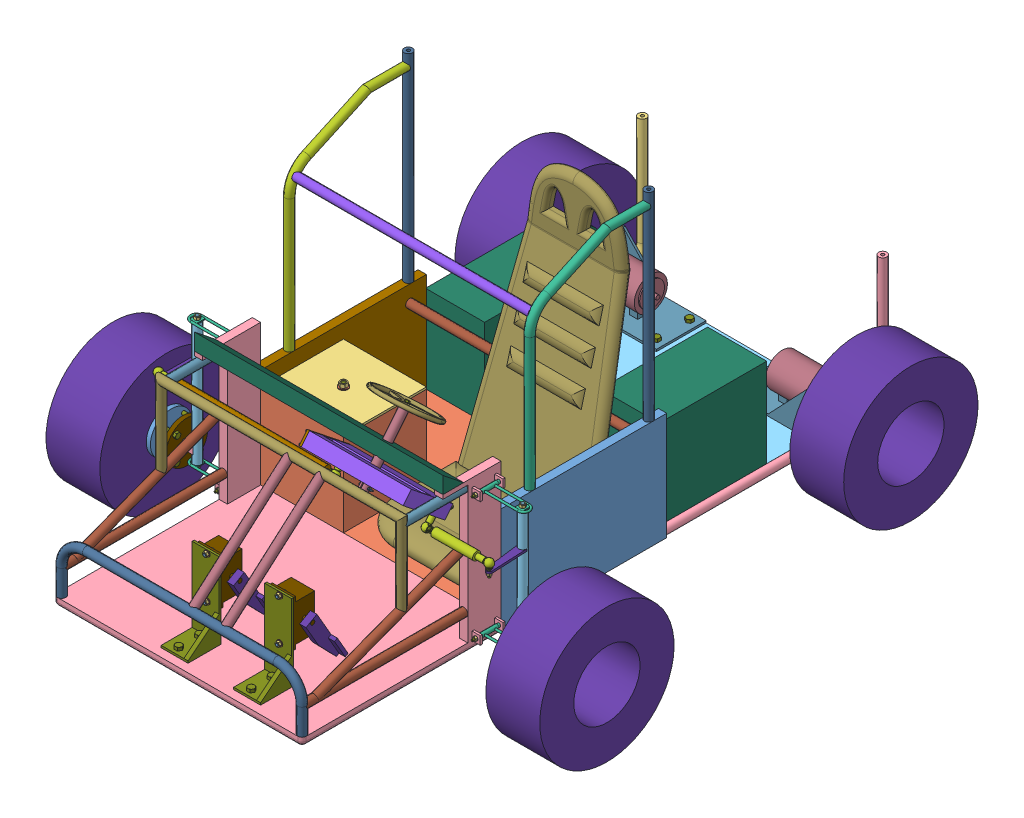
SolidWorks assembly Full_Assembly_2.0, configuration Default. Lengths in mm.
Overall size (1513.16 1181.12 1856.74).
253 component instances, 57 part files, 73 mates.
Components (placement in the parent):
- MC (1)-1: MC (1) [Default] at (-134.0082 207.4417 1496.2137) size (1191.26 1083.62 1343.85)
  - SPL-1: SPL [Default] at (646.5449 178.7927 -996.551) size (25.4 330.2 508)
  - BP-1: BP [Default] at (111.0665 -124.6065 -917.4807) size (711.2 25.4 508)
  - BBR-2: BBR [Default] at (-77.3551 -47.0728 -1647.3326) x (-1 0 0) z (0 -1 0) size (25.4 687.13 407.73)
  - BBL-1: BBL [Default] at (659.2449 -47.0728 -1647.3326) x (-1 0 0) z (0 -1 0) size (25.4 687.13 407.73)
  - BC-1: BC [Default] at (357.2961 -116.9228 -1647.3326) x (-1 0 0) z (0 0 -1) size (723.9 12.7 609.6)
  - FTL-1: FTL [Default] at (659.245 611.9935 -719.4116) x (0 -0.899323 -0.437285) z (-1 0 -0.000001) size (433.75 589.6 27.41)
  - FTR-1: FTR [Default] at (-77.355 611.9935 -719.4116) x (0 -0.899323 -0.437285) z (-1 0 -0.000001) size (433.75 589.6 27.38)
  - TC-1: TC [Default] at (652.8949 660.2535 -644.2461) x (0 -0.542655 -0.839955) z (-1 0 -0.000001) size (25.4 25.4 723.9)
  - SPR-1: SPR [Default] at (-90.0551 178.7927 -996.551) size (25.4 330.2 508)
  - BT-1: BT [Default] at (-77.3551 205.5935 -995.2506) x (0.000001 0 -1) z (1 0 0.000001) size (25.4 609.6 25.4)
  - BT-2: BT [Default] at (659.2449 205.5935 -995.2506) x (0.000001 0 -1) z (1 0 0.000001) size (25.4 609.6 25.4)
  - FB-1: FB [Default] at (-71.0051 154.7935 -986.9326) x (1 0 0) z (0 0.990518 0.137381) size (723.9 25.4 25.4)
  - seat-1: seat [Default] at (418.0013 -99.2065 -848.8249) size (437.03 835.23 478.09)
  - EA1-1: EA1 [Default] at (125.7912 -160.5315 -1631.3403) x (0 0 1) z (-1 0 0) size (411.48 411.48 1349.16)
    - EB1-1: EB1 [Default] at (60.2077 126.1588 196.7963) size (101.6 101.6 238.25)
    - EP1-1: EP1 [Default] at (60.2077 56.3088 69.7963) x (0 0 1) z (-1 0 0) size (254 133.35 152.4)
    - EA2-1: EA2 [Default] at (45.9187 58.6487 138.5565) size (411.48 411.48 213.36)
      - EP2-1: EP2 [Default] at (14.289 67.5101 114.1198) size (127 127 48.26)
      - hex bolt_ai-1: hex bolt_ai [HBOLT 0.4375-20x1.375x1.125-N] at (-36.511 67.5101 106.0934) x (0 0 1) z (-0.866025 -0.5 0) size (42.95 18.33 15.88)
      - hex bolt_ai-2: hex bolt_ai [HBOLT 0.4375-20x1.375x1.125-N] at (14.289 118.3101 106.0934) x (0 0 1) z (0 -1 0) size (42.95 18.33 15.88)
      - hex bolt_ai-3: hex bolt_ai [HBOLT 0.4375-20x1.375x1.125-N] at (14.289 16.7101 106.0934) x (0 0 1) z (-0.866025 0.5 0) size (42.95 18.33 15.88)
      - hex bolt_ai-4: hex bolt_ai [HBOLT 0.4375-20x1.375x1.125-N] at (65.089 67.5101 106.0934) x (0 0 1) z (-0.866025 0.5 0) size (42.95 18.33 15.88)
      - EB2-1: EB2 [Default] at (14.289 67.5101 129.9948) x (-1 0 0) z (0 0 -1) size (411.48 411.48 165.1)
      - flat washer type a wide_ai-1: flat washer type a wide_ai [Preferred Wide FW 0.4375] at (-36.511 67.5101 132.103) x (0 0 1) z (-0.923728 -0.383049 0) size (2.11 31.75 31.75)
      - flat washer type a wide_ai-2: flat washer type a wide_ai [Preferred Wide FW 0.4375] at (14.289 118.3101 132.103) x (0 0 1) z (1 0 0) size (2.11 31.75 31.75)
      - flat washer type a wide_ai-3: flat washer type a wide_ai [Preferred Wide FW 0.4375] at (14.289 16.7101 132.103) x (0 0 1) z (1 0 0) size (2.11 31.75 31.75)
      - flat washer type a wide_ai-4: flat washer type a wide_ai [Preferred Wide FW 0.4375] at (65.089 67.5101 132.103) x (0 0 1) z (1 0 0) size (2.11 31.75 31.75)
      - hex thick nut_ai-1: hex thick nut_ai [HTNUT 0.4375-14-D-N] at (14.289 16.7101 143.8632) x (0.055202 -0.998475 0) z (0 0 1) size (17.48 20.18 11.76)
      - hex thick nut_ai-2: hex thick nut_ai [HTNUT 0.4375-14-D-N] at (-36.511 67.5101 143.8632) x (0.547044 -0.837104 0) z (0 0 1) size (17.48 20.18 11.76)
      - hex thick nut_ai-3: hex thick nut_ai [HTNUT 0.4375-14-D-N] at (65.089 67.5101 143.8632) x (-0.982324 -0.18719 0) z (0 0 1) size (17.48 20.18 11.76)
      - hex thick nut_ai-4: hex thick nut_ai [HTNUT 0.4375-14-D-N] at (14.289 118.3101 143.8632) x (0.055202 -0.998475 0) z (0 0 1) size (17.48 20.18 11.76)
    - hex bolt_ai-8: hex bolt_ai [HBOLT 0.3125-18x1.375x0.875-N] at (17.0277 169.3388 215.4653) x (0 0 -1) z (0 1 0) size (40.89 14.66 12.7)
    - hex bolt_ai-9: hex bolt_ai [HBOLT 0.3125-18x1.375x0.875-N] at (103.3877 169.3388 215.4653) x (0 0 -1) z (0.866025 -0.5 0) size (40.89 14.66 12.7)
    - hex bolt_ai-10: hex bolt_ai [HBOLT 0.3125-18x1.375x0.875-N] at (103.3877 82.9788 215.4653) x (0 0 -1) z (0.866025 0.5 0) size (40.89 14.66 12.7)
    - hex bolt_ai-11: hex bolt_ai [HBOLT 0.3125-18x1.375x0.875-N] at (17.0277 82.9788 215.4653) x (0 0 -1) z (-0.866025 -0.5 0) size (40.89 14.66 12.7)
    - flat washer type a narrow_ai-1: flat washer type a narrow_ai [Preferred Narrow FW 0.3125] at (17.0277 169.3388 190.4463) x (0 0 1) z (-1 0 0) size (1.65 17.48 17.48)
    - flat washer type a narrow_ai-2: flat washer type a narrow_ai [Preferred Narrow FW 0.3125] at (103.3877 82.9788 190.4463) x (0 0 1) z (-1 0 0) size (1.65 17.48 17.48)
    - flat washer type a narrow_ai-3: flat washer type a narrow_ai [Preferred Narrow FW 0.3125] at (17.0277 82.9788 188.7953) x (0 0 -1) z (1 0 0) size (1.65 17.48 17.48)
    - flat washer type a narrow_ai-4: flat washer type a narrow_ai [Preferred Narrow FW 0.3125] at (103.3877 169.3388 188.7953) x (0 0 -1) z (0.923728 0.383049 0) size (1.65 17.48 17.48)
    - hex thick nut_ai-1: hex thick nut_ai [HTNUT 0.3125-18-D-N] at (103.3877 169.3388 188.7953) x (0.866025 0.5 0) z (0 0 1) size (12.7 14.66 8.53)
    - hex thick nut_ai-2: hex thick nut_ai [HTNUT 0.3125-18-D-N] at (17.0277 82.9788 180.2609) x (-0.866025 0.5 0) z (0 0 -1) size (12.7 14.66 8.53)
    - hex thick nut_ai-3: hex thick nut_ai [HTNUT 0.3125-18-D-N] at (103.3877 82.9788 181.9119) x (-0.866025 -0.5 0) z (0 0 -1) size (12.7 14.66 8.53)
    - hex thick nut_ai-4: hex thick nut_ai [HTNUT 0.3125-18-D-N] at (17.0277 169.3388 180.2609) x (-0.866025 -0.5 0) z (0 0 -1) size (12.7 14.66 8.53)
  - EA1-2: EA1 [Default] at (456.0986 -160.5315 -1510.9249) x (0 0 -1) z (1 0 0) size (411.48 411.48 1349.16)
    - EB1-1: EB1 [Default] at (60.2077 126.1588 196.7963) size (101.6 101.6 238.25)
    - EP1-1: EP1 [Default] at (60.2077 56.3088 69.7963) x (0 0 1) z (-1 0 0) size (254 133.35 152.4)
    - EA2-1: EA2 [Default] at (45.9187 58.6487 138.5565) size (411.48 411.48 213.36)
      - EP2-1: EP2 [Default] at (14.289 67.5101 114.1198) size (127 127 48.26)
      - hex bolt_ai-1: hex bolt_ai [HBOLT 0.4375-20x1.375x1.125-N] at (-36.511 67.5101 106.0934) x (0 0 1) z (-0.866025 -0.5 0) size (42.95 18.33 15.88)
      - hex bolt_ai-2: hex bolt_ai [HBOLT 0.4375-20x1.375x1.125-N] at (14.289 118.3101 106.0934) x (0 0 1) z (0 -1 0) size (42.95 18.33 15.88)
      - hex bolt_ai-3: hex bolt_ai [HBOLT 0.4375-20x1.375x1.125-N] at (14.289 16.7101 106.0934) x (0 0 1) z (-0.866025 0.5 0) size (42.95 18.33 15.88)
      - hex bolt_ai-4: hex bolt_ai [HBOLT 0.4375-20x1.375x1.125-N] at (65.089 67.5101 106.0934) x (0 0 1) z (-0.866025 0.5 0) size (42.95 18.33 15.88)
      - EB2-1: EB2 [Default] at (14.289 67.5101 129.9948) x (-1 0 0) z (0 0 -1) size (411.48 411.48 165.1)
      - flat washer type a wide_ai-1: flat washer type a wide_ai [Preferred Wide FW 0.4375] at (-36.511 67.5101 132.103) x (0 0 1) z (-0.923728 -0.383049 0) size (2.11 31.75 31.75)
      - flat washer type a wide_ai-2: flat washer type a wide_ai [Preferred Wide FW 0.4375] at (14.289 118.3101 132.103) x (0 0 1) z (1 0 0) size (2.11 31.75 31.75)
      - flat washer type a wide_ai-3: flat washer type a wide_ai [Preferred Wide FW 0.4375] at (14.289 16.7101 132.103) x (0 0 1) z (1 0 0) size (2.11 31.75 31.75)
      - flat washer type a wide_ai-4: flat washer type a wide_ai [Preferred Wide FW 0.4375] at (65.089 67.5101 132.103) x (0 0 1) z (1 0 0) size (2.11 31.75 31.75)
      - hex thick nut_ai-1: hex thick nut_ai [HTNUT 0.4375-14-D-N] at (14.289 16.7101 143.8632) x (0.055202 -0.998475 0) z (0 0 1) size (17.48 20.18 11.76)
      - hex thick nut_ai-2: hex thick nut_ai [HTNUT 0.4375-14-D-N] at (-36.511 67.5101 143.8632) x (0.547044 -0.837104 0) z (0 0 1) size (17.48 20.18 11.76)
      - hex thick nut_ai-3: hex thick nut_ai [HTNUT 0.4375-14-D-N] at (65.089 67.5101 143.8632) x (-0.982324 -0.18719 0) z (0 0 1) size (17.48 20.18 11.76)
      - hex thick nut_ai-4: hex thick nut_ai [HTNUT 0.4375-14-D-N] at (14.289 118.3101 143.8632) x (0.055202 -0.998475 0) z (0 0 1) size (17.48 20.18 11.76)
    - hex bolt_ai-8: hex bolt_ai [HBOLT 0.3125-18x1.375x0.875-N] at (17.0277 169.3388 215.4653) x (0 0 -1) z (0 1 0) size (40.89 14.66 12.7)
    - hex bolt_ai-9: hex bolt_ai [HBOLT 0.3125-18x1.375x0.875-N] at (103.3877 169.3388 215.4653) x (0 0 -1) z (0.866025 -0.5 0) size (40.89 14.66 12.7)
    - hex bolt_ai-10: hex bolt_ai [HBOLT 0.3125-18x1.375x0.875-N] at (103.3877 82.9788 215.4653) x (0 0 -1) z (0.866025 0.5 0) size (40.89 14.66 12.7)
    - hex bolt_ai-11: hex bolt_ai [HBOLT 0.3125-18x1.375x0.875-N] at (17.0277 82.9788 215.4653) x (0 0 -1) z (-0.866025 -0.5 0) size (40.89 14.66 12.7)
    - flat washer type a narrow_ai-1: flat washer type a narrow_ai [Preferred Narrow FW 0.3125] at (17.0277 169.3388 190.4463) x (0 0 1) z (-1 0 0) size (1.65 17.48 17.48)
    - flat washer type a narrow_ai-2: flat washer type a narrow_ai [Preferred Narrow FW 0.3125] at (103.3877 82.9788 190.4463) x (0 0 1) z (-1 0 0) size (1.65 17.48 17.48)
    - flat washer type a narrow_ai-3: flat washer type a narrow_ai [Preferred Narrow FW 0.3125] at (17.0277 82.9788 188.7953) x (0 0 -1) z (1 0 0) size (1.65 17.48 17.48)
    - flat washer type a narrow_ai-4: flat washer type a narrow_ai [Preferred Narrow FW 0.3125] at (103.3877 169.3388 188.7953) x (0 0 -1) z (0.923728 0.383049 0) size (1.65 17.48 17.48)
    - hex thick nut_ai-1: hex thick nut_ai [HTNUT 0.3125-18-D-N] at (103.3877 169.3388 188.7953) x (0.866025 0.5 0) z (0 0 1) size (12.7 14.66 8.53)
    - hex thick nut_ai-2: hex thick nut_ai [HTNUT 0.3125-18-D-N] at (17.0277 82.9788 180.2609) x (-0.866025 0.5 0) z (0 0 -1) size (12.7 14.66 8.53)
    - hex thick nut_ai-3: hex thick nut_ai [HTNUT 0.3125-18-D-N] at (103.3877 82.9788 181.9119) x (-0.866025 -0.5 0) z (0 0 -1) size (12.7 14.66 8.53)
    - hex thick nut_ai-4: hex thick nut_ai [HTNUT 0.3125-18-D-N] at (17.0277 169.3388 180.2609) x (-0.866025 -0.5 0) z (0 0 -1) size (12.7 14.66 8.53)
  - hex bolt_ai-1: hex bolt_ai [HBOLT 0.5000-13x1.375x1.25-N] at (157.5949 -88.6272 -1621.9326) x (0 -1 0) z (-1 0 0) size (44.17 22 19.05)
  - hex bolt_ai-2: hex bolt_ai [HBOLT 0.5000-13x1.375x1.25-N] at (157.5949 -88.6272 -1520.3326) x (0 -1 0) z (0.5 0 -0.866025) size (44.17 22 19.05)
  - hex bolt_ai-3: hex bolt_ai [HBOLT 0.5000-13x1.375x1.25-N] at (424.2949 -88.6272 -1520.3326) x (0 -1 0) z (1 0 0) size (44.17 22 19.05)
  - hex bolt_ai-4: hex bolt_ai [HBOLT 0.5000-13x1.375x1.25-N] at (602.0949 -88.6272 -1621.9326) x (0 -1 0) z (-0.5 0 -0.866025) size (44.17 22 19.05)
  - hex bolt_ai-5: hex bolt_ai [HBOLT 0.5000-13x1.375x1.25-N] at (424.2949 -88.6272 -1621.9326) x (0 -1 0) z (0.5 0 -0.866025) size (44.17 22 19.05)
  - hex bolt_ai-6: hex bolt_ai [HBOLT 0.5000-13x1.375x1.25-N] at (602.0949 -88.6272 -1520.3326) x (0 -1 0) z (-0.5 0 0.866025) size (44.17 22 19.05)
  - hex bolt_ai-7: hex bolt_ai [HBOLT 0.5000-13x1.375x1.25-N] at (-20.2051 -88.6272 -1621.9326) x (0 -1 0) z (-1 0 0) size (44.17 22 19.05)
  - hex bolt_ai-8: hex bolt_ai [HBOLT 0.5000-13x1.375x1.25-N] at (-20.2051 -88.6272 -1520.3326) x (0 -1 0) z (1 0 0) size (44.17 22 19.05)
  - flat washer type a wide_ai-1: flat washer type a wide_ai [Preferred Wide FW 0.5] at (157.5949 -119.6914 -1520.3326) x (0 -1 0) z (0.546944 0 -0.837169) size (2.77 34.92 34.92)
  - flat washer type a wide_ai-2: flat washer type a wide_ai [Preferred Wide FW 0.5] at (157.5949 -119.6914 -1621.9326) x (0 -1 0) z (0.967366 0 0.253384) size (2.77 34.92 34.92)
  - flat washer type a wide_ai-3: flat washer type a wide_ai [Preferred Wide FW 0.5] at (424.2949 -119.6914 -1621.9326) x (0 -1 0) z (-0.558017 0 -0.829829) size (2.77 34.92 34.92)
  - flat washer type a wide_ai-4: flat washer type a wide_ai [Preferred Wide FW 0.5] at (-20.2051 -119.6914 -1520.3326) x (0 -1 0) z (0.590888 0 -0.806754) size (2.77 34.92 34.92)
  - flat washer type a wide_ai-5: flat washer type a wide_ai [Preferred Wide FW 0.5] at (602.0949 -119.6914 -1520.3326) x (0 -1 0) z (0.610265 0 -0.792197) size (2.77 34.92 34.92)
  - flat washer type a wide_ai-6: flat washer type a wide_ai [Preferred Wide FW 0.5] at (424.2949 -119.6914 -1520.3326) x (0 -1 0) z (0.837672 0 -0.546174) size (2.77 34.92 34.92)
  - flat washer type a wide_ai-7: flat washer type a wide_ai [Preferred Wide FW 0.5] at (602.0949 -119.6914 -1621.9326) x (0 -1 0) z (0.97172 0 -0.236136) size (2.77 34.92 34.92)
  - flat washer type a wide_ai-8: flat washer type a wide_ai [Preferred Wide FW 0.5] at (-20.2051 -119.6914 -1621.9326) x (0 -1 0) z (0.345214 0 -0.938524) size (2.77 34.92 34.92)
  - hex nut_ai-1: hex nut_ai [HNUT 0.5000-13-D-N] at (157.5949 -131.0706 -1520.3326) x (-0.5 0 -0.866025) z (0 -1 0) size (19.05 22 11.38)
  - hex nut_ai-2: hex nut_ai [HNUT 0.5000-13-D-N] at (-20.2051 -131.0706 -1621.9326) x (-0.866025 0 -0.5) z (0 -1 0) size (19.05 22 11.38)
  - hex nut_ai-3: hex nut_ai [HNUT 0.5000-13-D-N] at (-20.2051 -131.0706 -1520.3326) x (0 0 -1) z (0 -1 0) size (19.05 22 11.38)
  - hex nut_ai-4: hex nut_ai [HNUT 0.5000-13-D-N] at (157.5949 -131.0706 -1621.9326) x (0 0 -1) z (0 -1 0) size (19.05 22 11.38)
  - hex nut_ai-5: hex nut_ai [HNUT 0.5000-13-D-N] at (424.2949 -131.0706 -1520.3326) x (0 0 1) z (0 -1 0) size (19.05 22 11.38)
  - hex nut_ai-6: hex nut_ai [HNUT 0.5000-13-D-N] at (424.2949 -131.0706 -1621.9326) x (-0.866025 0 0.5) z (0 -1 0) size (19.05 22 11.38)
  - hex nut_ai-8: hex nut_ai [HNUT 0.5000-13-D-N] at (602.0949 -131.0706 -1520.3326) x (-0.866025 0 -0.5) z (0 -1 0) size (19.05 22 11.38)
  - hex nut_ai-9: hex nut_ai [HNUT 0.5000-13-D-N] at (602.0949 -131.0706 -1621.9326) x (-0.866025 0 -0.5) z (0 -1 0) size (19.05 22 11.38)
  - hex bolt_ai-11: hex bolt_ai [HBOLT 0.5000-13x3x1.25-N] at (62.3449 -133.8521 -656.7326) x (0 1 0) z (-0.5 0 0.866025) size (85.45 22 19.05)
  - flat washer type a narrow_ai-1: flat washer type a narrow_ai [Preferred Narrow FW 0.5] at (62.3449 -99.2065 -656.7326) x (0 -1 0) z (0 0 1) size (2.41 26.97 26.97)
  - hex nut_ai-10: hex nut_ai [HNUT 0.5000-13-D-N] at (62.3449 -87.8273 -656.7326) x (1 0 0) z (0 1 0) size (19.05 22 11.38)
- FCA1-1: FCA1 [Default] at (-224.0632 159.0352 1576.0811) size (1513.16 852.83 849.49)
  - FCP1-1: FCP1 [Default] at origin size (812.8 457.2 609.6)
  - STA1-2: STA1 [Default] at (558.8 334.6162 -409.4012) x (-0.999987 0.003219 0.004024) z (0 0.780869 -0.624695) size (320.68 259.28 240.21)
    - STP10-3: STP10 [Default] at origin size (304.8 155.79 25.4)
      - spur gear_ai-4: spur gear_ai [Inch - Spur gear 6DP 25T 20PA 1FW ---S25N3.0H2.0L1.0S1] x (0 0 1) z (-0.989908 0.141715 0) size (25.4 113.98 114.2)
      - rack spur rectangular_ai-2: rack spur rectangular_ai [Inch - Rack-spur - rectangular 6DP 20PA 1FW 1.5PH 12L---SAll] at (-154.037 -91.44 25.4) size (304.8 42.33 25.4)
    - STP01-11: STP01 [Default] at (138.063 -75.0375 -39.3517) x (0 1 0) z (0 0 -1) size (23.88 20.07 47.75)
    - STP03-3: STP03 [Default] at (150.763 -97.79 31.75) x (0 0 -1) z (1 0 0) size (39.69 165.1 311.15)
    - STP04-3: STP04 [Default] at (150.763 -97.79 -7.9375) x (0 0 1) z (-1 0 0) size (39.69 165.1 6.59)
    - socket head cap screw_ai-1: socket head cap screw_ai [HX-SHCS 0.125-40x0.5x0.5-N] at (160.288 64.135 28.575) x (-1 0 0) z (0 0.866025 0.5) size (15.88 5.21 5.21)
    - socket head cap screw_ai-2: socket head cap screw_ai [HX-SHCS 0.125-40x0.5x0.5-N] at (160.288 64.135 -4.7625) x (-1 0 0) z (0 0.866025 0.5) size (15.88 5.21 5.21)
    - socket head cap screw_ai-4: socket head cap screw_ai [HX-SHCS 0.125-40x0.5x0.5-N] at (160.288 -94.615 28.575) x (-1 0 0) z (0 0.866025 0.5) size (15.88 5.21 5.21)
    - socket head cap screw_ai-7: socket head cap screw_ai [HX-SHCS 0.125-40x0.5x0.5-N] at (160.288 -94.615 -4.7625) x (-1 0 0) z (0 0.866025 0.5) size (15.88 5.21 5.21)
    - STP01-10: STP01 [Default] at (-141.337 -75.0375 -39.3517) x (0 -1 0) z (0 0 -1) size (23.88 20.07 47.75)
    - STP05-2: STP05 [Default] at (-154.037 -58.6317 0) x (1 0 0) z (0 0 -1) size (304.8 32.77 26.99)
    - STP06-1: STP06 [Default] at (-0.0036 -0.0251 180.975) x (0.5 -0.866025 0) z (0 0 1) size (189.81 189.81 12.01)
    - STP07-1: STP07 [Default] at (-0.0036 -0.0251 -33.528) x (-0.141715 -0.989908 0) z (0 0 1) size (28 24.77 211.33)
    - FWP4-1: FWP4 [Default] at (-20.7057 3.2593 -20.828) x (0 0 1) z (0.989908 -0.141715 0) size (12.7 12.7 39.95)
    - hex bolt_ai-1: hex bolt_ai [HBOLT 0.2500-20x0.75x0.75-N] at (-0.0036 -0.0251 188.9252) x (0 0 -1) z (0.5 0.866025 0) size (23.83 12.85 11.13)
  - STP08-1: STP08 [Default] at (469.9 381 -431.8) x (0 0 -1) z (1 0 0) size (63.5 50.8 762)
  - STP02-1: STP02 [Default] at (889.5958 256.5577 -445.8437) x (-0.961205 0 0.275836) z (0 1 0) size (16.51 16.51 46.05)
  - SP3-1: SP3 [Default] at (889.5958 238.8316 -445.8437) x (-0.086724 0 -0.996232) z (0 -1 0) size (120.39 25.32 6.35)
  - FWA1-1: FWA1 [Default] at (1025.989 75.5387 -589.4868) x (0 -0.682582 -0.730809) z (-1 0 0) size (411.48 411.48 257.81)
    - FWP5-2: FWP5 [Default] at (27.9791 75.0582 101.7677) size (127 127 48.26)
    - FWP1-1: FWP1 [Default] at (27.9791 75.0582 53.5077) size (127 127 48.26)
    - EB2-1: EB2 [Default] at (27.9791 75.0582 50.3327) x (-1 0 0) z (0 0 1) size (411.48 411.48 165.1)
    - internal tooth-lock washers_ai-1: internal tooth-lock washers_ai [Internal Tooth LW Type A-0.375] at (78.7791 75.0582 49.3167) x (0.992449 -0.122662 0) z (-0.122662 -0.992449 0) size (17.58 1.02 17.58)
    - internal tooth-lock washers_ai-2: internal tooth-lock washers_ai [Internal Tooth LW Type A-0.375] at (-22.8209 75.0582 49.3167) x (0.730809 -0.682582 0) z (-0.682582 -0.730809 0) size (17.58 1.02 17.58)
    - FWP2-2: FWP2 [Default] at (27.9791 75.0582 114.4677) x (-0.730809 0.682582 0) z (0 0 -1) size (9.53 9.53 14.29)
    - FWP3-2: FWP3 [Default] at (19.3103 65.7769 130.3427) x (0 0 1) z (-0.730809 0.682582 0) size (31.75 25.4 25.4)
    - FWP4-1: FWP4 [Default] at (13.8923 59.9761 123.9927) x (-0.730809 0.682582 0) z (0.682582 0.730809 0) size (12.7 12.7 39.95)
    - hex nut_ai-5: hex nut_ai [HNUT 0.4375-20-D-N] at (78.7791 75.0582 49.3167) x (0.291608 -0.956538 0) z (0 0 1) size (17.48 20.18 9.78)
    - internal tooth-lock washers_ai-5: internal tooth-lock washers_ai [Internal Tooth LW Type A-0.375] at (27.9791 24.2582 49.3167) x (-0.875007 -0.484111 0) z (-0.484111 0.875007 0) size (17.58 1.02 17.58)
    - internal tooth-lock washers_ai-6: internal tooth-lock washers_ai [Internal Tooth LW Type A-0.375] at (27.9791 125.8582 49.3167) x (0.730809 -0.682582 0) z (-0.682582 -0.730809 0) size (17.58 1.02 17.58)
    - hex nut_ai-7: hex nut_ai [HNUT 0.4375-20-D-N] at (-22.8209 75.0582 49.3167) x (0.291608 -0.956538 0) z (0 0 1) size (17.48 20.18 9.78)
    - hex nut_ai-8: hex nut_ai [HNUT 0.4375-20-D-N] at (27.9791 24.2582 39.5377) x (-0.97419 0.225729 0) z (0 0 -1) size (17.48 20.18 9.78)
    - hex nut_ai-9: hex nut_ai [HNUT 0.4375-20-D-N] at (27.9791 125.8582 49.3167) x (-0.97419 0.225729 0) z (0 0 1) size (17.48 20.18 9.78)
    - hex bolt_ai-1: hex bolt_ai [HBOLT 0.4375-20x3x1.125-N] at (78.7791 75.0582 122.4941) x (0 0 -1) z (-0.291608 0.956538 0) size (84.23 18.33 15.88)
    - hex bolt_ai-2: hex bolt_ai [HBOLT 0.4375-20x3x1.125-N] at (27.9791 125.8582 122.4941) x (0 0 -1) z (0.682582 0.730809 0) size (84.23 18.33 15.88)
    - hex bolt_ai-3: hex bolt_ai [HBOLT 0.4375-20x3x1.125-N] at (-22.8209 75.0582 122.4941) x (0 0 -1) z (0.97419 -0.225729 0) size (84.23 18.33 15.88)
    - hex bolt_ai-6: hex bolt_ai [HBOLT 0.4375-20x3x1.125-N] at (27.9791 24.2582 122.4941) x (0 0 -1) z (0.97419 -0.225729 0) size (84.23 18.33 15.88)
  - SA1-3: SA1 [Default] at (902.3249 84.601 -573.897) x (-0.581832 0 -0.813309) z (0 1 0) size (129.23 145.39 403.48)
    - SS1-1: SS1 [Default] at (0.7633 27.1847 256.5845) x (1 0 0) z (0 0 1) size (25.4 25.4 403.48)
    - SP2-2: SP2 [Default] at (87.3872 94.4048 258.172) x (0.581832 0.813309 0) z (-0.813309 0.581832 0) size (133.34 12.7 63.5)
    - SP2-3: SP2 [Default] at (87.3872 94.4048 -122.701) x (0.581832 0.813309 0) z (-0.813309 0.581832 0) size (133.34 12.7 63.5)
    - hex nut_ai-3: hex nut_ai [HNUT 0.3750-24-D-N] at (0.7633 27.1846 -132.8483) x (0.910536 0.41343 0) z (0 0 -1) size (14.27 16.48 8.56)
    - hex nut_ai-4: hex nut_ai [HNUT 0.3750-24-D-N] at (0.7633 27.1847 268.3193) x (0.910536 0.41343 0) z (0 0 1) size (14.27 16.48 8.56)
  - STP09-1: STP09 [Default] at (724.7148 240.1747 -456.9263) x (0.009813 0 0.999952) z (-0.999952 0 0.009813) size (25.4 25.4 152.4)
  - STP02-2: STP02 [Default] at (699.7485 256.5577 -443.9807) x (-0.004906 -0.866025 -0.499976) z (-0.999952 0 0.009813) size (16.51 16.51 46.05)
  - STP01-3: STP01 [Default] at (889.5958 256.5577 -445.8437) x (0.009813 0 0.999952) z (0.999952 0 -0.009813) size (23.88 20.07 47.75)
  - hex bolt_ai-1: hex bolt_ai [HBOLT 0.2500-20x3.5x0.75-N] at (774.7 342.9 -601.6752) x (0 0 1) z (-1 0 0) size (93.68 12.85 11.13)
  - external tooth lock washer_ai-1: external tooth lock washer_ai [ASME B18.21.1 - 0.256] at (774.7 342.9 -520.7) x (0 0 -1) z (0.999649 0.026486 0) size (0.58 12.4 12.55)
  - hex nut_ai-1: hex nut_ai [HNUT 0.2500-28-D-N] at (774.7 342.9 -514.3754) x (0.5 -0.866025 0) z (0 0 1) size (11.11 12.83 5.74)
  - hex bolt_ai-2: hex bolt_ai [HBOLT 0.2500-20x3.5x0.75-N] at (774.7 -38.1 -601.6752) x (0 0 1) z (-0.5 0.866025 0) size (93.68 12.85 11.13)
  - external tooth lock washer_ai-2: external tooth lock washer_ai [ASME B18.21.1 - 0.256] at (774.7 -38.1 -520.7) x (0 0 -1) z (0.643979 -0.765044 0) size (0.58 12.4 12.55)
  - hex nut_ai-2: hex nut_ai [HNUT 0.2500-28-D-N] at (774.7 -38.1 -514.3754) x (0.5 -0.866025 0) z (0 0 1) size (11.11 12.83 5.74)
  - FWA1-2: FWA1 [Default] at (-263.989 -72.2367 -589.4868) x (0 0.682582 -0.730809) z (1 0 0) size (411.48 411.48 257.81)
    - FWP5-2: FWP5 [Default] at (27.9791 75.0582 101.7677) size (127 127 48.26)
    - FWP1-1: FWP1 [Default] at (27.9791 75.0582 53.5077) size (127 127 48.26)
    - EB2-1: EB2 [Default] at (27.9791 75.0582 50.3327) x (-1 0 0) z (0 0 1) size (411.48 411.48 165.1)
    - internal tooth-lock washers_ai-1: internal tooth-lock washers_ai [Internal Tooth LW Type A-0.375] at (78.7791 75.0582 49.3167) x (0.992449 -0.122662 0) z (-0.122662 -0.992449 0) size (17.58 1.02 17.58)
    - internal tooth-lock washers_ai-2: internal tooth-lock washers_ai [Internal Tooth LW Type A-0.375] at (-22.8209 75.0582 49.3167) x (0.730809 -0.682582 0) z (-0.682582 -0.730809 0) size (17.58 1.02 17.58)
    - FWP2-2: FWP2 [Default] at (27.9791 75.0582 114.4677) x (-0.730809 0.682582 0) z (0 0 -1) size (9.53 9.53 14.29)
    - FWP3-2: FWP3 [Default] at (19.3103 65.7769 130.3427) x (0 0 1) z (-0.730809 0.682582 0) size (31.75 25.4 25.4)
    - FWP4-1: FWP4 [Default] at (13.8923 59.9761 123.9927) x (-0.730809 0.682582 0) z (0.682582 0.730809 0) size (12.7 12.7 39.95)
    - hex nut_ai-5: hex nut_ai [HNUT 0.4375-20-D-N] at (78.7791 75.0582 49.3167) x (0.291608 -0.956538 0) z (0 0 1) size (17.48 20.18 9.78)
    - internal tooth-lock washers_ai-5: internal tooth-lock washers_ai [Internal Tooth LW Type A-0.375] at (27.9791 24.2582 49.3167) x (-0.875007 -0.484111 0) z (-0.484111 0.875007 0) size (17.58 1.02 17.58)
    - internal tooth-lock washers_ai-6: internal tooth-lock washers_ai [Internal Tooth LW Type A-0.375] at (27.9791 125.8582 49.3167) x (0.730809 -0.682582 0) z (-0.682582 -0.730809 0) size (17.58 1.02 17.58)
    - hex nut_ai-7: hex nut_ai [HNUT 0.4375-20-D-N] at (-22.8209 75.0582 49.3167) x (0.291608 -0.956538 0) z (0 0 1) size (17.48 20.18 9.78)
    - hex nut_ai-8: hex nut_ai [HNUT 0.4375-20-D-N] at (27.9791 24.2582 39.5377) x (-0.97419 0.225729 0) z (0 0 -1) size (17.48 20.18 9.78)
    - hex nut_ai-9: hex nut_ai [HNUT 0.4375-20-D-N] at (27.9791 125.8582 49.3167) x (-0.97419 0.225729 0) z (0 0 1) size (17.48 20.18 9.78)
    - hex bolt_ai-1: hex bolt_ai [HBOLT 0.4375-20x3x1.125-N] at (78.7791 75.0582 122.4941) x (0 0 -1) z (-0.291608 0.956538 0) size (84.23 18.33 15.88)
    - hex bolt_ai-2: hex bolt_ai [HBOLT 0.4375-20x3x1.125-N] at (27.9791 125.8582 122.4941) x (0 0 -1) z (0.682582 0.730809 0) size (84.23 18.33 15.88)
    - hex bolt_ai-3: hex bolt_ai [HBOLT 0.4375-20x3x1.125-N] at (-22.8209 75.0582 122.4941) x (0 0 -1) z (0.97419 -0.225729 0) size (84.23 18.33 15.88)
    - hex bolt_ai-6: hex bolt_ai [HBOLT 0.4375-20x3x1.125-N] at (27.9791 24.2582 122.4941) x (0 0 -1) z (0.97419 -0.225729 0) size (84.23 18.33 15.88)
  - SA1-4: SA1 [Default] at (-140.3249 220.199 -573.897) x (0.581832 0 -0.813309) z (0 -1 0) size (129.23 145.39 403.48)
    - SS1-1: SS1 [Default] at (0.7633 27.1847 256.5845) x (1 0 0) z (0 0 1) size (25.4 25.4 403.48)
    - SP2-2: SP2 [Default] at (87.3872 94.4048 258.172) x (0.581832 0.813309 0) z (-0.813309 0.581832 0) size (133.34 12.7 63.5)
    - SP2-3: SP2 [Default] at (87.3872 94.4048 -122.701) x (0.581832 0.813309 0) z (-0.813309 0.581832 0) size (133.34 12.7 63.5)
    - hex nut_ai-3: hex nut_ai [HNUT 0.3750-24-D-N] at (0.7633 27.1846 -132.8483) x (0.910536 0.41343 0) z (0 0 -1) size (14.27 16.48 8.56)
    - hex nut_ai-4: hex nut_ai [HNUT 0.3750-24-D-N] at (0.7633 27.1847 268.3193) x (0.910536 0.41343 0) z (0 0 1) size (14.27 16.48 8.56)
  - hex bolt_ai-4: hex bolt_ai [HBOLT 0.2500-20x3.5x0.75-N] at (-12.7 342.9 -601.6752) x (0 0 1) z (-1 0 0) size (93.68 12.85 11.13)
  - external tooth lock washer_ai-9: external tooth lock washer_ai [ASME B18.21.1 - 0.256] at (-12.7 342.9 -520.7) x (0 0 -1) z (0.602564 -0.798071 0) size (0.58 12.4 12.55)
  - hex nut_ai-3: hex nut_ai [HNUT 0.2500-28-D-N] at (-12.7 342.9 -514.3754) size (11.11 12.83 5.74)
  - SP3-2: SP3 [Default] at (-123.1466 232.2195 -445.5445) x (0.047449 0 -0.998874) z (0 1 0) size (120.39 25.32 6.35)
  - hex nut_ai-4: hex nut_ai [HNUT 0.3125-24-D-N] at (889.5958 225.5474 -445.8437) x (0.986789 0 0.162012) z (0 -1 0) size (12.7 14.66 6.93)
  - STP010-1: STP010 [Default] at (395.2241 278.1416 -442.6472) x (-0.002815 -0.625306 0.780375) z (0.999986 0.00167 0.004946) size (25.4 25.4 508)
  - STP02-3: STP02 [Default] at (420.3522 257.4571 -442.8565) x (0.004395 -0.780378 -0.625293) z (0.999986 0.00167 0.004946) size (16.51 16.51 46.05)
  - STP02-4: STP02 [Default] at (-123.1466 256.5497 -445.5445) x (0.666341 0 0.745647) z (0 1 0) size (16.51 16.51 46.05)
  - hex nut_ai-5: hex nut_ai [HNUT 0.3125-24-D-N] at (-123.1466 225.2853 -445.5445) x (-0.977382 0 -0.211483) z (0 -1 0) size (12.7 14.66 6.93)
  - STP01-5: STP01 [Default] at (-123.1466 256.5497 -445.5445) x (0.005218 -0.342016 -0.93968) z (-0.999986 -0.00167 -0.004946) size (23.88 20.07 47.75)
  - hex bolt_ai-5: hex bolt_ai [HBOLT 0.2500-20x3.5x0.75-N] at (-12.7 -37.973 -601.6752) x (0 0 1) z (-1 0 0) size (93.68 12.85 11.13)
  - external tooth lock washer_ai-10: external tooth lock washer_ai [ASME B18.21.1 - 0.256] at (-12.7 -37.973 -520.7) x (0 0 -1) z (0.999649 -0.026486 0) size (0.58 12.4 12.55)
  - hex nut_ai-6: hex nut_ai [HNUT 0.2500-28-D-N] at (-12.7 -37.973 -520.1158) x (0.5 0.866025 0) z (0 0 -1) size (11.11 12.83 5.74)
  - FCP2-1: FCP2 [Default] at (12.7 -50.8 -12.7) size (762 168.4 25.4)
  - FCP3-1: FCP3 [Default] at (12.7 25.4 -508) x (0.992649 -0.121026 0) z (0 0 1) size (25.4 25.4 495.3)
  - FCP3-2: FCP3 [Default] at (749.3 25.4 -508) size (25.4 25.4 495.3)
  - FCP3-4: FCP3 [Default] at (12.7 25.4 -50.8) x (0.846332 0.498186 0.188503) z (0 0.353892 -0.935286) size (25.4 25.4 495.3)
  - FCP4-1: FCP4 [Default] at (12.7 127 -317.5) size (762 254 25.4)
  - FCP3-6: FCP3 [Default] at (749.3 200.6828 -514.0473) x (1 0 0) z (0 -0.353892 0.935286) size (25.4 25.4 495.3)
  - FCP5-1: FCP5 [Default] at (408.6538 104.14 -15.24) x (1 0 0) z (0 -0.658057 0.752969) size (25.4 25.4 401.32)
  - FCP5-2: FCP5 [Default] at (508 104.14 -15.24) x (1 0 0) z (0 -0.658057 0.752969) size (25.4 25.4 401.32)
  - FCP6-1: FCP6 [Default] at (749.3 355.6 -508) size (25.4 25.4 190.5)
  - FCP6-2: FCP6 [Default] at (12.7 355.6 -508) size (25.4 25.4 190.5)
- EB3-1: EB3 [Default] at (-201.2514 239.236 293.8891) x (0 0 -1) z (1 0 0) size (329.18 272.03 181.1)
- EB3-2: EB3 [Default] at (515.1249 239.236 293.8891) x (0 0 1) z (-1 0 0) size (329.18 272.03 181.1)
- EA4-1: EA4 [Default] at (112.4728 224.5389 1520.8381) x (-1 0 0) z (0 0 -1) size (143.05 262.66 260.65)
  - EB5-1: EB5 [Default] at (-114.2478 -116.3037 -29.843) size (82.55 234.95 101.6)
  - EA3-1: EA3 [Default] at (-6.3794 -155.1404 121.9178) x (-1 0 0) z (0 0.866025 -0.5) size (143.05 125.43 222.11)
    - EB4_2-1: EB4_2 [Default] at (50.3684 86.3483 116.5793) size (58.1 38.1 153)
    - EB4_1-1: EB4_1 [Default] at (-27.6316 86.3483 185.4593) x (0 0.5 0.866025) z (1 0 0) size (140 64 124)
  - t-head bolt_ai-1: t-head bolt_ai [TBOLT 0.3125-18x0.875x0.875-N] at (-14.7478 110.1463 84.107) x (0 0 -1) z (0 -1 0) size (28.57 15.67 7.94)
  - t-head bolt_ai-2: t-head bolt_ai [TBOLT 0.3125-18x0.875x0.875-N] at (-14.7478 -17.1037 84.107) x (0 0 -1) z (0 -1 0) size (28.57 15.67 7.94)
  - flat washer type a narrow_ai-1: flat washer type a narrow_ai [Preferred Narrow FW 0.3125] at (-14.7478 -17.1037 63.756) x (0 0 -1) z (0.923728 0.383049 0) size (1.65 17.48 17.48)
  - flat washer type a narrow_ai-2: flat washer type a narrow_ai [Preferred Narrow FW 0.3125] at (-14.7478 110.1463 63.756) x (0 0 -1) z (0.923728 0.383049 0) size (1.65 17.48 17.48)
  - hex nut_ai-1: hex nut_ai [HNUT 0.3125-18-D-N] at (-14.7478 110.1463 63.756) x (0.866025 -0.5 0) z (0 0 1) size (12.7 14.66 6.93)
  - hex nut_ai-2: hex nut_ai [HNUT 0.3125-18-D-N] at (-14.7478 -17.1037 63.756) x (0.866025 -0.5 0) z (0 0 1) size (12.7 14.66 6.93)
- EA4-2: EA4 [Default] at (334.7889 224.5389 1520.8381) x (-1 0 0) z (0 0 -1) size (143.05 262.66 260.65)
  - EB5-1: EB5 [Default] at (-114.2478 -116.3037 -29.843) size (82.55 234.95 101.6)
  - EA3-1: EA3 [Default] at (-6.3794 -155.1404 121.9178) x (-1 0 0) z (0 0.866025 -0.5) size (143.05 125.43 222.11)
    - EB4_2-1: EB4_2 [Default] at (50.3684 86.3483 116.5793) size (58.1 38.1 153)
    - EB4_1-1: EB4_1 [Default] at (-27.6316 86.3483 185.4593) x (0 0.5 0.866025) z (1 0 0) size (140 64 124)
  - t-head bolt_ai-1: t-head bolt_ai [TBOLT 0.3125-18x0.875x0.875-N] at (-14.7478 110.1463 84.107) x (0 0 -1) z (0 -1 0) size (28.57 15.67 7.94)
  - t-head bolt_ai-2: t-head bolt_ai [TBOLT 0.3125-18x0.875x0.875-N] at (-14.7478 -17.1037 84.107) x (0 0 -1) z (0 -1 0) size (28.57 15.67 7.94)
  - flat washer type a narrow_ai-1: flat washer type a narrow_ai [Preferred Narrow FW 0.3125] at (-14.7478 -17.1037 63.756) x (0 0 -1) z (0.923728 0.383049 0) size (1.65 17.48 17.48)
  - flat washer type a narrow_ai-2: flat washer type a narrow_ai [Preferred Narrow FW 0.3125] at (-14.7478 110.1463 63.756) x (0 0 -1) z (0.923728 0.383049 0) size (1.65 17.48 17.48)
  - hex nut_ai-1: hex nut_ai [HNUT 0.3125-18-D-N] at (-14.7478 110.1463 63.756) x (0.866025 -0.5 0) z (0 0 1) size (12.7 14.66 6.93)
  - hex nut_ai-2: hex nut_ai [HNUT 0.3125-18-D-N] at (-14.7478 -17.1037 63.756) x (0.866025 -0.5 0) z (0 0 1) size (12.7 14.66 6.93)
- hex bolt_ai-1: hex bolt_ai [HBOLT 0.5000-13x1.875x1.25-N] at (115.5956 123.8308 1531.6311) x (0 -1 0) z (0 0 1) size (56.87 22 19.05)
- hex bolt_ai-2: hex bolt_ai [HBOLT 0.5000-13x1.875x1.25-N] at (337.9118 123.8308 1531.6311) x (0 -1 0) z (0 0 1) size (56.87 22 19.05)
- hex bolt_ai-3: hex bolt_ai [HBOLT 0.5000-13x1.875x1.25-N] at (337.9118 123.8308 1468.1311) x (0 -1 0) z (-0.866025 0 -0.5) size (56.87 22 19.05)
- hex bolt_ai-4: hex bolt_ai [HBOLT 0.5000-13x1.875x1.25-N] at (115.5956 123.8308 1468.1311) x (0 -1 0) z (0 0 1) size (56.87 22 19.05)
- flat washer type a narrow_ai-1: flat washer type a narrow_ai [Preferred Narrow FW 0.5] at (337.9118 82.8352 1468.1311) x (0 1 0) z (0.940911 0 0.338655) size (2.41 26.97 26.97)
- flat washer type a narrow_ai-2: flat washer type a narrow_ai [Preferred Narrow FW 0.5] at (337.9118 80.4222 1531.6311) x (0 -1 0) z (0.5 0 0.866025) size (2.41 26.97 26.97)
- flat washer type a narrow_ai-3: flat washer type a narrow_ai [Preferred Narrow FW 0.5] at (115.5956 80.4222 1531.6311) x (0 -1 0) z (-0.546944 0 0.837169) size (2.41 26.97 26.97)
- flat washer type a narrow_ai-4: flat washer type a narrow_ai [Preferred Narrow FW 0.5] at (115.5956 80.4222 1468.1311) x (0 -1 0) z (-0.546944 0 0.837169) size (2.41 26.97 26.97)
- hex nut_ai-1: hex nut_ai [HNUT 0.5000-13-D-N] at (115.5956 80.4222 1468.1311) x (0 0 -1) z (0 1 0) size (19.05 22 11.38)
- hex nut_ai-2: hex nut_ai [HNUT 0.5000-13-D-N] at (337.9118 69.043 1468.1311) x (0.866025 0 0.5) z (0 -1 0) size (19.05 22 11.38)
- hex nut_ai-3: hex nut_ai [HNUT 0.5000-13-D-N] at (337.9118 69.043 1531.6311) x (0.866025 0 -0.5) z (0 -1 0) size (19.05 22 11.38)
- hex nut_ai-4: hex nut_ai [HNUT 0.5000-13-D-N] at (115.5956 69.043 1531.6311) x (0.866025 0 0.5) z (0 -1 0) size (19.05 22 11.38)
- hex bolt_ai-8: hex bolt_ai [HBOLT 0.5000-13x3x1.25-N] at (375.9255 154.0462 784.0565) x (0 -1 0) z (0 0 1) size (85.45 22 19.05)
- hex bolt_ai-9: hex bolt_ai [HBOLT 0.5000-13x3x1.25-N] at (192.0608 154.0462 784.0565) x (0 -1 0) z (-0.866025 0 0.5) size (85.45 22 19.05)
- flat washer type a narrow_ai-5: flat washer type a narrow_ai [Preferred Narrow FW 0.5] at (192.0608 80.4222 784.0565) x (0 -1 0) z (-0.88596 0 0.463763) size (2.41 26.97 26.97)
- flat washer type a narrow_ai-6: flat washer type a narrow_ai [Preferred Narrow FW 0.5] at (375.9255 80.4222 784.0565) x (0 -1 0) z (-0.025683 0 0.99967) size (2.41 26.97 26.97)
- hex nut_ai-5: hex nut_ai [HNUT 0.5000-13-D-N] at (375.9255 71.456 784.0565) x (1 0 0) z (0 -1 0) size (19.05 22 11.38)
- hex nut_ai-6: hex nut_ai [HNUT 0.5000-13-D-N] at (192.0608 71.456 784.0565) x (1 0 0) z (0 -1 0) size (19.05 22 11.38)
- EA5-1: EA5 [Default] at (-4.6103 125.1358 543.8474) size (254 872.68 254)
  - EP3-1: EP3 [Default] at (-67.0529 -16.9006 295.6337) size (254 254 254)
  - EP4-1: EP4 [Default] at (-67.0529 237.0994 295.6337) x (0 0 1) z (-1 0 0) size (254 6.35 254)
  - hex bolt_ai-1: hex bolt_ai [HBOLT 0.5000-13x1x1-N] at (-67.0529 221.5038 295.6337) x (0 1 0) z (0 0 1) size (34.65 22 19.05)
  - flat washer type a narrow_ai-1: flat washer type a narrow_ai [Preferred Narrow FW 0.5] at (-67.0529 245.8624 295.6337) x (0 1 0) z (-0.546944 0 0.837169) size (2.41 26.97 26.97)
  - hex nut_ai-3: hex nut_ai [HNUT 0.5000-13-D-N] at (-67.0529 257.2416 295.6337) x (1 0 0) z (0 1 0) size (19.05 22 11.38)
Mates (geometry in assembly coordinates):
- Coincident1: coincident: plane of MC (1)-1/BP-1 through (-198.6632 108.2352 966.4811) normal (0 0 1); plane of FCA1-1/FCP1-1 through (-224.0632 159.0352 966.4811) normal (0 0 -1)
- Coincident2: coincident: plane of MC (1)-1/SPL-1 through (537.9368 413.0352 966.4811) normal (0 0 1); plane of FCA1-1/FCP1-1 through (-224.0632 159.0352 966.4811) normal (0 0 -1)
- Coincident3: coincident: plane of MC (1)-1/SPL-1 through (537.9368 413.0352 966.4811) normal (0 0 1); plane of FCA1-1/FCP1-1 through (-224.0632 159.0352 966.4811) normal (0 0 -1)
- Coincident4: coincident: line of MC (1)-1/SPR-1 through (-224.0632 413.0352 966.4811) axis (0 -1 0); line of FCA1-1/FCP1-1 through (-224.0632 540.0352 966.4811) axis (0 -1 0)
- Coincident6: coincident: line of MC (1)-1/BP-1 through (-198.6632 82.8352 966.4811) axis (1 0 0); line of FCA1-1/FCP1-1 through (525.2368 82.8352 966.4811) axis (-1 0 0)
- Coincident7: coincident: plane of MC (1)-1/BC-1 through (223.2879 103.219 -151.1189) normal (0 1 0); plane of EB3-1 through (-20.1494 103.219 458.4811) normal (0 -1 0)
- Coincident8: coincident: line of MC (1)-1/BBR-2 through (-201.2514 103.219 458.4811) axis (0 0 -1); line of EB3-1 through (-201.2514 103.219 458.4811) axis (0 0 -1)
- Parallel3: parallel: line of MC (1)-1/SPR-1 through (-198.6632 82.8352 458.4811) axis (0 1 0); line of EB3-1 through (-201.2514 375.253 458.4811) axis (0 -1 0)
- Coincident13: coincident: plane of MC (1)-1/BP-1 through (-198.6632 108.2352 458.4811) normal (0 0 -1); plane of EB3-1 through (-20.1494 375.253 458.4811) normal (0 0 1)
- Coincident14: coincident: plane of MC (1)-1/BC-1 through (223.2879 103.219 -151.1189) normal (0 1 0); plane of EB3-2 through (334.0229 103.219 129.2971) normal (0 -1 0)
- Coincident15: coincident: line of MC (1)-1/BBL-1 through (515.1249 103.219 -151.1189) axis (0 0 1); line of EB3-2 through (515.1249 103.219 129.2971) axis (0 0 1)
- Coincident16: coincident: plane of MC (1)-1/BP-1 through (-198.6632 108.2352 458.4811) normal (0 0 -1); plane of EB3-2 through (334.0229 375.253 458.4811) normal (0 0 1)
- Coincident17: coincident: plane of FCA1-1/FCP1-1 through (-224.0632 108.2352 1550.6811) normal (0 1 0); plane of EA4-1/EB5-1 through (80.6706 108.2352 1550.6811) normal (0 -1 0)
- Parallel4: parallel: line of MC (1)-1/BP-1 through (-198.6632 108.2352 966.4811) axis (1 0 0); line of EA4-1/EB5-1 through (80.6706 108.2352 1449.0811) axis (1 0 0)
- Distance2: distance = 482.6 mm: line of EA4-1/EB5-1 through (80.6706 108.2352 1449.0811) axis (1 0 0); line of FCA1-1/FCP1-1 through (512.5368 108.2352 966.4811) axis (-1 0 0)
- Parallel5: parallel: line of FCA1-1/FCP1-1 through (537.9368 108.2352 1563.3811) axis (0 0 -1); line of EA4-1/EB5-1 through (163.2206 108.2352 1550.6811) axis (0 0 -1)
- Distance3: distance = 304.8 mm: line of EA4-1/EB5-1 through (80.6706 114.5852 1550.6811) axis (0 0 -1); line of FCA1-1/FCP1-1 through (-224.0632 108.2352 1563.3811) axis (0 0 -1)
- Coincident22: coincident: plane of FCA1-1/FCP1-1 through (-224.0632 108.2352 1550.6811) normal (0 1 0); plane of EA4-2/EB5-1 through (302.9868 108.2352 1550.6811) normal (0 -1 0)
- Parallel6: parallel: line of FCA1-1/FCP1-1 through (512.5368 108.2352 966.4811) axis (-1 0 0); line of EA4-2/EB5-1 through (302.9868 108.2352 1449.0811) axis (1 0 0)
- Parallel7: parallel: line of FCA1-1/FCP1-1 through (537.9368 108.2352 1563.3811) axis (0 0 -1); line of EA4-2/EB5-1 through (385.5368 108.2352 1550.6811) axis (0 0 -1)
- Distance4: distance = 482.6 mm: line of FCA1-1/FCP1-1 through (512.5368 108.2352 966.4811) axis (-1 0 0); line of EA4-2/EB5-1 through (302.9868 108.2352 1449.0811) axis (1 0 0)
- Distance5: distance = 152.4 mm: line of EA4-2/EB5-1 through (385.5368 108.2352 1550.6811) axis (0 0 -1); line of FCA1-1/FCP1-1 through (537.9368 108.2352 1563.3811) axis (0 0 -1)
- Concentric1: concentric: cylinder of EA4-2/EB5-1 through (337.9118 101.8852 1468.1311) axis (0 1 0) radius 6.35; cylinder of hex bolt_ai-3 through (337.9118 123.8308 1468.1311) axis (0 1 0) radius 6.35
- Coincident27: coincident: plane of EA4-2/EB5-1 through (302.9868 114.5852 1550.6811) normal (0 1 0); plane of hex bolt_ai-3 through (332.4125 114.5852 1477.6561) normal (0 -1 0)
- Parallel8: parallel: plane of FCA1-1/FCP1-1 through (-224.0632 159.0352 1576.0811) normal (0 0 1); plane of hex bolt_ai-3 through (343.411 114.5852 1477.6561) normal (0 0 1)
- Concentric2: concentric: cylinder of hex bolt_ai-3 through (337.9118 123.8308 1468.1311) axis (0 1 0) radius 6.35; cylinder of flat washer type a narrow_ai-1 through (337.9118 47.9102 1468.1311) axis (0 -1 0) radius 6.7437
- Coincident29: coincident: plane of FCA1-1/FCP1-1 through (-224.0632 82.8352 2341.8816) normal (0 -1 0); plane of flat washer type a narrow_ai-1 through (335.628 82.8352 1474.4763) normal (0 1 0)
- Concentric4: concentric: cylinder of hex bolt_ai-3 through (337.9118 123.8308 1468.1311) axis (0 1 0) radius 6.35; cylinder of hex nut_ai-2 through (337.9118 80.4222 1468.1311) axis (0 -1 0) radius 5.3581
- Coincident31: coincident: plane of flat washer type a narrow_ai-1 through (333.3442 80.4222 1480.8215) normal (0 -1 0); plane of hex nut_ai-2 through (321.414 80.4222 1458.6061) normal (0 1 0)
- Parallel9: parallel: line of FCA1-1/FCP1-1 through (525.2368 82.8352 1563.3811) axis (-1 0 0); plane of hex nut_ai-2 through (343.411 80.4222 1477.6561) normal (0 0 1)
- Concentric5: concentric: cylinder of FCA1-1/FCP1-1 through (337.9118 -130.1684 1531.6311) axis (0 1 0) radius 6.35; cylinder of hex bolt_ai-2 through (337.9118 123.8308 1531.6311) axis (0 1 0) radius 6.35
- Coincident33: coincident: plane of EA4-2/EB5-1 through (302.9868 114.5852 1550.6811) normal (0 1 0); plane of hex bolt_ai-2 through (348.9103 114.5852 1531.6311) normal (0 -1 0)
- Parallel10: parallel: plane of FCA1-1/FCP1-1 through (-224.0632 159.0352 1576.0811) normal (0 0 1); plane of hex bolt_ai-2 through (343.411 114.5852 1541.1561) normal (0 0 1)
- Concentric6: concentric: cylinder of hex bolt_ai-2 through (337.9118 123.8308 1531.6311) axis (0 1 0) radius 6.35; cylinder of flat washer type a narrow_ai-2 through (337.9118 115.3472 1531.6311) axis (0 1 0) radius 6.7437
- Coincident35: coincident: plane of FCA1-1/FCP1-1 through (-224.0632 82.8352 2341.8816) normal (0 -1 0); plane of flat washer type a narrow_ai-2 through (349.5922 82.8352 1524.8874) normal (0 1 0)
- Concentric7: concentric: cylinder of hex bolt_ai-2 through (337.9118 123.8308 1531.6311) axis (0 1 0) radius 6.35; cylinder of hex nut_ai-3 through (337.9118 80.4222 1531.6311) axis (0 -1 0) radius 5.3581
- Coincident36: coincident: plane of flat washer type a narrow_ai-2 through (343.752 80.4222 1528.2593) normal (0 -1 0); plane of hex nut_ai-3 through (321.414 80.4222 1541.1561) normal (0 1 0)
- Parallel11: parallel: plane of FCA1-1/FCP1-1 through (-224.0632 159.0352 1576.0811) normal (0 0 1); plane of hex nut_ai-3 through (343.411 80.4222 1541.1561) normal (0 0 1)
- Concentric8: concentric: cylinder of FCA1-1/FCP1-1 through (115.5956 -130.1684 1531.6311) axis (0 1 0) radius 6.35; cylinder of hex bolt_ai-1 through (115.5956 123.8308 1531.6311) axis (0 1 0) radius 6.35
- Coincident38: coincident: plane of EA4-1/EB5-1 through (80.6706 114.5852 1550.6811) normal (0 1 0); plane of hex bolt_ai-1 through (126.5941 114.5852 1531.6311) normal (0 -1 0)
- Parallel12: parallel: plane of FCA1-1/FCP1-1 through (-224.0632 159.0352 1576.0811) normal (0 0 1); plane of hex bolt_ai-1 through (121.0949 114.5852 1541.1561) normal (0 0 1)
- Concentric9: concentric: cylinder of hex bolt_ai-1 through (115.5956 123.8308 1531.6311) axis (0 1 0) radius 6.35; cylinder of flat washer type a narrow_ai-3 through (115.5956 115.3472 1531.6311) axis (0 1 0) radius 6.7437
- Coincident40: coincident: plane of FCA1-1/FCP1-1 through (-224.0632 82.8352 2341.8816) normal (0 -1 0); plane of flat washer type a narrow_ai-3 through (126.8869 82.8352 1539.008) normal (0 1 0)
- Concentric10: concentric: cylinder of hex bolt_ai-1 through (115.5956 123.8308 1531.6311) axis (0 1 0) radius 6.35; cylinder of hex nut_ai-4 through (115.5956 80.4222 1531.6311) axis (0 -1 0) radius 5.3581
- Coincident41: coincident: plane of flat washer type a narrow_ai-3 through (121.2412 80.4222 1535.3195) normal (0 -1 0); plane of hex nut_ai-4 through (99.0978 80.4222 1522.1061) normal (0 1 0)
- Parallel13: parallel: plane of FCA1-1/FCP1-1 through (-224.0632 159.0352 1576.0811) normal (0 0 1); plane of hex nut_ai-4 through (121.0949 80.4222 1541.1561) normal (0 0 1)
- Concentric11: concentric: cylinder of FCA1-1/FCP1-1 through (115.5956 -130.1684 1468.1311) axis (0 1 0) radius 6.35; cylinder of hex bolt_ai-4 through (115.5956 123.8308 1468.1311) axis (0 1 0) radius 6.35
- Coincident43: coincident: plane of EA4-1/EB5-1 through (80.6706 114.5852 1550.6811) normal (0 1 0); plane of hex bolt_ai-4 through (126.5941 114.5852 1468.1311) normal (0 -1 0)
- Parallel14: parallel: plane of FCA1-1/FCP1-1 through (-224.0632 159.0352 1576.0811) normal (0 0 1); plane of hex bolt_ai-4 through (121.0949 114.5852 1477.6561) normal (0 0 1)
- Concentric12: concentric: cylinder of hex bolt_ai-4 through (115.5956 123.8308 1468.1311) axis (0 1 0) radius 6.35; cylinder of flat washer type a narrow_ai-4 through (115.5956 115.3472 1468.1311) axis (0 1 0) radius 6.7437
- Coincident45: coincident: plane of FCA1-1/FCP1-1 through (-224.0632 82.8352 2341.8816) normal (0 -1 0); plane of flat washer type a narrow_ai-4 through (126.8869 82.8352 1475.508) normal (0 1 0)
- Concentric13: concentric: cylinder of hex bolt_ai-4 through (115.5956 123.8308 1468.1311) axis (0 1 0) radius 6.35; cylinder of hex nut_ai-1 through (115.5956 69.043 1468.1311) axis (0 1 0) radius 5.3581
- Coincident46: coincident: plane of flat washer type a narrow_ai-4 through (121.2412 80.4222 1471.8195) normal (0 -1 0); plane of hex nut_ai-1 through (115.5956 80.4222 1487.1811) normal (0 1 0)
- Parallel15: parallel: plane of FCA1-1/FCP1-1 through (-224.0632 159.0352 1576.0811) normal (0 0 1); plane of hex nut_ai-1 through (110.0964 69.043 1477.6561) normal (0 0 1)
- Concentric14: concentric: cylinder of MC (1)-1/seat-1 through (192.0608 -130.1684 784.0565) axis (0 1 0) radius 6.35; cylinder of hex bolt_ai-9 through (192.0608 154.0462 784.0565) axis (0 1 0) radius 6.35
- Concentric15: concentric: cylinder of MC (1)-1/seat-1 through (375.9255 -130.1684 784.0565) axis (0 1 0) radius 6.35; cylinder of hex bolt_ai-8 through (375.9255 154.0462 784.0565) axis (0 1 0) radius 6.35
- Coincident53: coincident: plane of MC (1)-1/seat-1 through (375.9255 144.8006 784.0565) normal (0 1 0); plane of hex bolt_ai-8 through (375.9255 144.8006 765.0065) normal (0 -1 0)
- Coincident54: coincident: plane of MC (1)-1/seat-1 through (192.0608 144.8006 784.0565) normal (0 1 0); plane of hex bolt_ai-9 through (208.5586 144.8006 774.5315) normal (0 -1 0)
- Parallel18: parallel: line of MC (1)-1/seat-1 through (181.7442 154.9606 840.9212) axis (1 0 0); plane of hex bolt_ai-9 through (197.56 144.8006 793.5815) normal (0 0 1)
- Parallel19: parallel: line of MC (1)-1/seat-1 through (181.7442 154.9606 840.9212) axis (1 0 0); plane of hex bolt_ai-8 through (381.4248 144.8006 793.5815) normal (0 0 1)
- Concentric16: concentric: cylinder of hex bolt_ai-8 through (375.9255 154.0462 784.0565) axis (0 1 0) radius 6.35; cylinder of flat washer type a narrow_ai-6 through (375.9255 115.3472 784.0565) axis (0 1 0) radius 6.7437
- Concentric17: concentric: cylinder of hex bolt_ai-9 through (192.0608 154.0462 784.0565) axis (0 1 0) radius 6.35; cylinder of flat washer type a narrow_ai-5 through (192.0608 115.3472 784.0565) axis (0 1 0) radius 6.7437
- Coincident57: coincident: plane of MC (1)-1/BP-1 through (-22.9417 82.8352 578.733) normal (0 -1 0); plane of flat washer type a narrow_ai-6 through (389.4085 82.8352 784.4029) normal (0 1 0)
- Coincident58: coincident: plane of MC (1)-1/BP-1 through (-22.9417 82.8352 578.733) normal (0 -1 0); plane of flat washer type a narrow_ai-5 through (198.3157 82.8352 796.0058) normal (0 1 0)
- Coincident60: coincident: plane of MC (1)-1/BP-1 through (-22.9417 82.8352 578.733) normal (0 -1 0); plane of hex nut_ai-5 through (356.8755 82.8352 784.0565) normal (0 1 0)
- Concentric19: concentric: cylinder of hex bolt_ai-9 through (192.0608 154.0462 784.0565) axis (0 1 0) radius 6.35; cylinder of hex nut_ai-6 through (192.0608 96.4935 784.0565) axis (0 -1 0) radius 6.35
- Coincident61: coincident: plane of MC (1)-1/BP-1 through (-22.9417 82.8352 578.733) normal (0 -1 0); plane of hex nut_ai-6 through (173.0108 82.8352 784.0565) normal (0 1 0)
- Concentric20: concentric: cylinder of hex bolt_ai-8 through (375.9255 154.0462 784.0565) axis (0 1 0) radius 6.35; cylinder of hex nut_ai-5 through (375.9255 82.8352 784.0565) axis (0 -1 0) radius 5.3581
- Parallel20: parallel: plane of MC (1)-1/SPL-1 through (537.9368 386.2345 499.6627) normal (1 0 0); plane of hex nut_ai-5 through (385.4505 82.8352 789.5557) normal (1 0 0)
- Parallel21: parallel: plane of MC (1)-1/SPL-1 through (537.9368 386.2345 499.6627) normal (1 0 0); plane of hex nut_ai-6 through (201.5858 82.8352 789.5557) normal (1 0 0)
- Coincident62: coincident: plane of MC (1)-1/BP-1 through (-22.9417 108.2352 578.733) normal (0 1 0); plane of EA5-1/EP3-1 through (-71.6632 108.2352 839.4811) normal (0 -1 0)
- Coincident63: coincident: plane of MC (1)-1/SPR-1 through (-198.6632 386.2345 499.6627) normal (1 0 0); plane of EA5-1/EP3-1 through (-198.6632 362.2352 712.4811) normal (-1 0 0)
- Coincident64: coincident: line of MC (1)-1/BP-1 through (-198.6632 108.2352 966.4811) axis (1 0 0); line of EA5-1/EP3-1 through (-198.6632 108.2352 966.4811) axis (1 0 0)
